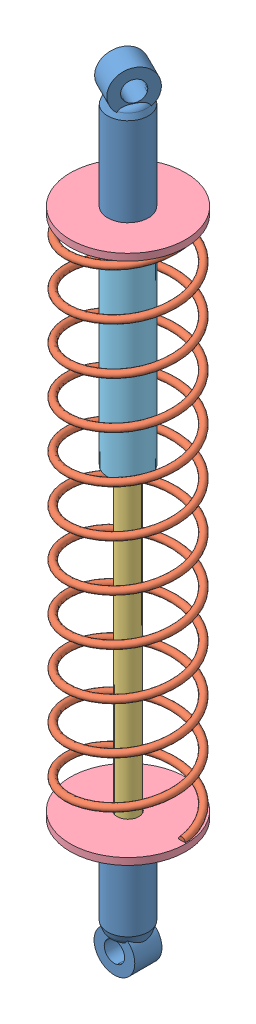
SolidWorks assembly suspension, configuration Default. Lengths in mm.
Overall size (24.03 116 24.03).
7 component instances, 5 part files, 15 mates.
Components (placement in the parent):
- ball joint-1: ball joint [Default] at (0 94 0) x (0.445011 0 -0.895525) z (0.895525 0 0.445011) size (6 19 6)
- ball joint-2: ball joint [Default] at (0 16 0) x (1 0 0) z (0 0 -1) size (6 19 6)
- Spring-1: Spring [Default] at (0 17 0) x (0.999949 0 -0.010147) z (0.010147 0 0.999949) size (17.22 53.54 19.28)
- suspension shaft-1: suspension shaft [Default] at (0 68 0) x (0.126267 0 -0.991996) z (-0.991996 0 -0.126267) size (3 65 3)
- washer-1: washer [Default] at (0 16 0) x (-0.681802 0 -0.731536) z (0.731536 0 -0.681802) size (17 1 17)
- washer-2: washer [Default] at (0 93 0) size (17 1 17)
- suspension shaft 1-1: suspension shaft 1 [Default] at (0 103 0) x (-0.837169 0 -0.546944) z (-0.546944 0 0.837169) size (6 42 6)
Mates (geometry in assembly coordinates):
- Concentric1: concentric aligned: cylinder of ball joint-2 through (0 3 0) axis (0 1 0) radius 3; cylinder of suspension shaft-1 through (0 3 0) axis (0 1 0) radius 1.5
- Concentric3: concentric aligned: cylinder of suspension shaft-1 through (0 3 0) axis (0 1 0) radius 1.5; circle of washer-1
- Coincident1: coincident anti-aligned: plane of ball joint-2 through (0 16 0) normal (0 1 0); plane of washer-1 through (0 16 0) normal (0 -1 0)
- Concentric4: concentric anti-aligned: cylinder of suspension shaft-1 through (0 3 0) axis (0 1 0) radius 1.5; cylinder of washer-2 through (0 94 0) axis (0 -1 0) radius 1.6
- Coincident2: coincident anti-aligned: plane of ball joint-1 through (0 94 0) normal (0 -1 0); plane of washer-2 through (0 94 0) normal (0 1 0)
- Concentric5: concentric anti-aligned: cylinder of ball joint-1 through (0 107 0) axis (0 -1 0) radius 3; cylinder of suspension shaft 1-1 through (0 93 0) axis (0 1 0) radius 1.5
- Coincident3: coincident anti-aligned: plane of washer-2 through (0 93 0) normal (0 -1 0); plane of suspension shaft 1-1 through (0 93 0) normal (0 1 0)
- Concentric6: concentric aligned: cylinder of suspension shaft-1 through (0 3 0) axis (0 1 0) radius 1.5; cylinder of suspension shaft 1-1 through (0 91 0) axis (0 1 0) radius 3
- Coincident4: coincident: point of ball joint-2
- Parallel1: parallel anti-aligned: plane of ball joint-2 through (0 0 -2) normal (0 0 -1)
- Coincident7: coincident: line of ball joint-2 through (3 0 -2) axis (-1 0 0)
- Coincident8: coincident anti-aligned: plane of Spring-1 through (0 17 0) normal (0 -1 0); plane of washer-1 through (0 17 0) normal (0 1 0)
- Concentric7: concentric aligned: line of Spring-1 through (51.5426 0 17) axis (0 0 1); cylinder of suspension shaft-1 through (0 3 0) axis (0 1 0) radius 1.5
- LimitDistance1: limit distance = 76 mm anti-aligned: plane of washer-1 through (0 17 0) normal (0 1 0); plane of washer-2 through (0 93 0) normal (0 -1 0)
- Coincident11: coincident anti-aligned: plane of ball joint-2 through (0 3 0) normal (0 1 0); plane of suspension shaft-1 through (0 3 0) normal (0 -1 0)
